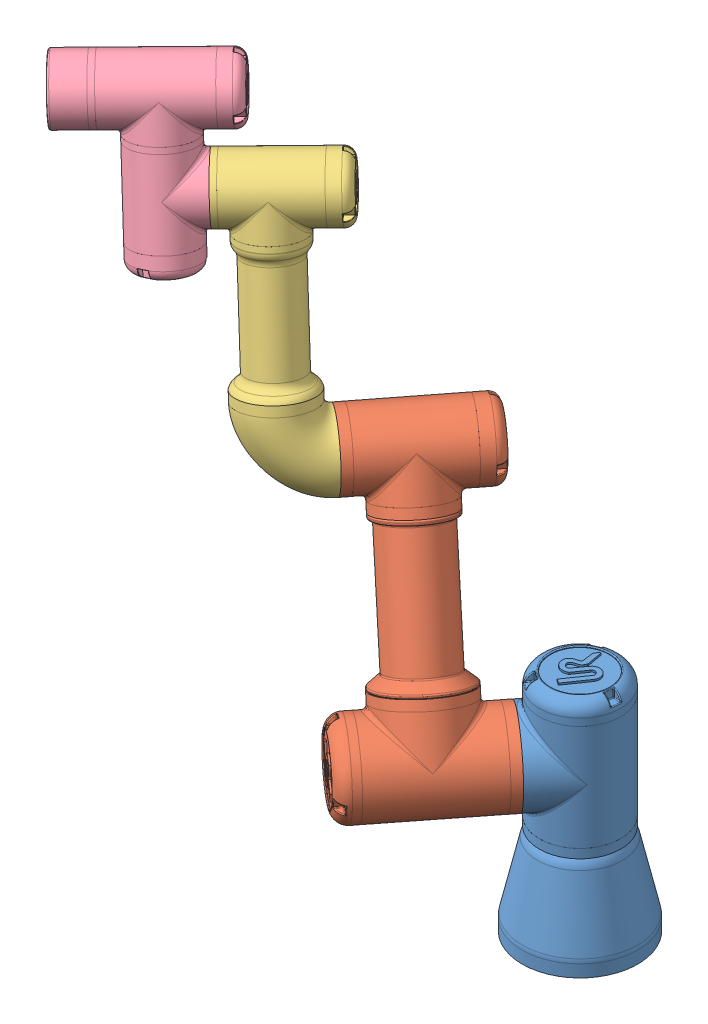
SolidWorks assembly UR simplified assembly, configuration Default. Lengths in mm.
Overall size (491.08 743.63 278.73).
4 component instances, 4 part files, 6 mates.
Components (placement in the parent):
- Base^UR3 Assembly-1: Base^UR3 Assembly [Default] at (143.5303 -28.8253 54.7093) size (131.37 250.8 133.51)
- Arm1^UR3 Assembly-1: Arm1^UR3 Assembly [Default] at (190.437 -50.4442 91.4176) x (0.970896 0.238416 -0.022776) z (-0.022776 0.186579 0.982176) size (166.12 336.5 176.79)
- Arm2^UR3 Assembly-1: Arm2^UR3 Assembly [Default] at (119.5642 -54.2773 37.0394) x (0.99673 0.080776 -0.002135) z (-0.00319 0.065728 0.997832) size (139.42 296.06 133.37)
- Arm3^UR3 Assembly-1: Arm3^UR3 Assembly [Default] at (106.496 -53.4377 22.8848) x (0.998113 0.061372 -0.001735) z (-0.001007 0.044616 0.999004) size (154.27 188.13 148.26)
Mates (geometry in assembly coordinates):
- Concentric1: concentric anti-aligned: cylinder of Base^UR3 Assembly-1 through (156.3392 152.4923 199.8158) axis (0.616294 0 -0.787516) radius 42.5; cylinder of Arm1^UR3 Assembly-1 through (159.4207 152.4923 195.8783) axis (-0.616294 0 0.787516) radius 45
- Coincident1: coincident anti-aligned: plane of Base^UR3 Assembly-1 through (156.3392 152.4923 199.8158) normal (-0.616294 0 0.787516); plane of Arm1^UR3 Assembly-1 through (156.3392 152.4923 199.8158) normal (0.616294 0 -0.787516)
- Concentric2: concentric anti-aligned: cylinder of Arm1^UR3 Assembly-1 through (5.0564 386.4981 228.7202) axis (-0.608864 0.00409 0.793264) radius 35; cylinder of Arm2^UR3 Assembly-1 through (-1.0322 386.539 236.6529) axis (0.608864 -0.00409 -0.793264) radius 35
- Coincident2: coincident anti-aligned: plane of Arm1^UR3 Assembly-1 through (2.0121 386.5185 232.6866) normal (-0.608864 0.00409 0.793264); plane of Arm2^UR3 Assembly-1 through (2.0121 386.5185 232.6866) normal (0.608864 -0.00409 -0.793264)
- Concentric3: concentric aligned: cylinder of Arm2^UR3 Assembly-1 through (-100.1911 603.0739 265.7879) axis (-0.735332 -0.038491 0.676613) radius 32.5; cylinder of Arm3^UR3 Assembly-1 through (-102.3971 602.9584 267.8178) axis (-0.735332 -0.038491 0.676613) radius 30
- Coincident3: coincident anti-aligned: plane of Arm2^UR3 Assembly-1 through (-102.3971 602.9584 267.8178) normal (-0.735332 -0.038491 0.676613); plane of Arm3^UR3 Assembly-1 through (-102.3971 602.9584 267.8178) normal (0.735332 0.038491 -0.676613)
